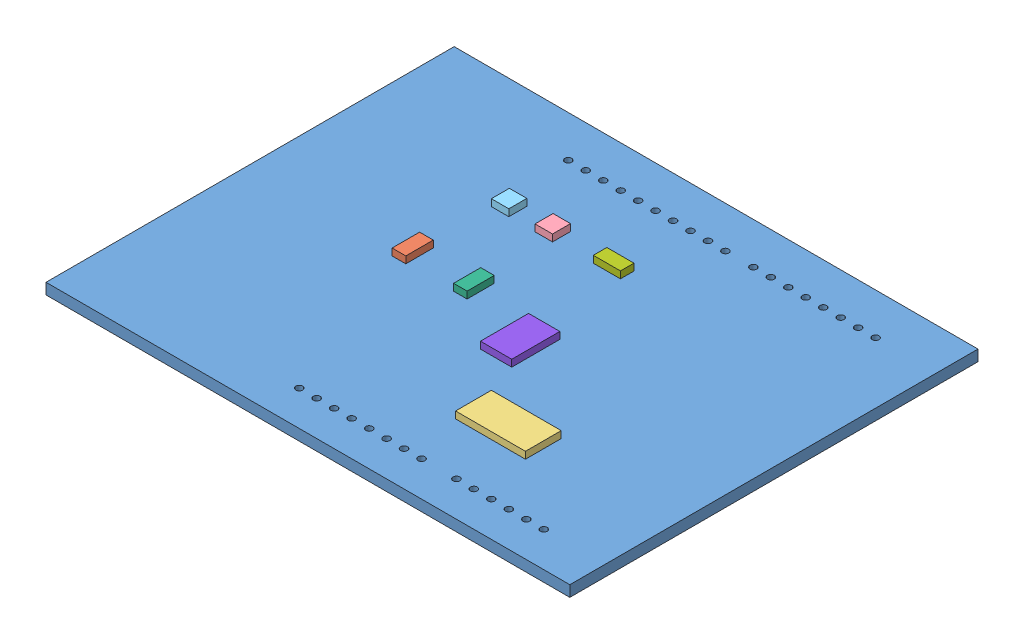
SolidWorks assembly PCB_Assembly, configuration Default. Lengths in mm.
Overall size (76.18 2.6 59.36).
8 component instances, 8 part files, 0 mates.
Components (placement in the parent):
- initial_schematic-1: initial_schematic [Default] x (1 0 0) z (0 1 0) size (76.18 59.36 1.6)
- C0805_C1_C0805-1: C0805_C1_C0805 [Default] at (57.15 1.6 -41.91) x (0 0 -1) z (0 1 0) size (4 1.99 1)
- AB9V_AB9V-1: AB9V_AB9V [Default] at (86.36 1.6 -26.67) x (0 0 -1) z (0 1 0) size (5.21 10.16 1)
- 1X01_JP1_1X01-1: 1X01_JP1_1X01 [Default] at (64.77 1.6 -54.61) x (1 0 0) z (0 1 0) size (2.54 2.62 1)
- 1X01_JP2_1X01-1: 1X01_JP2_1X01 [Default] at (58.42 1.6 -54.61) x (1 0 0) z (0 1 0) size (2.54 2.62 1)
- R0805W_50000-1: R0805W_50000 [Default] at (66.04 1.6 -41.91) x (0 0 1) z (0 1 0) size (3.95 1.97 1)
- R0805W_200-1: R0805W_200 [Default] at (73.66 1.6 -54.61) x (1 0 0) z (0 1 0) size (3.95 1.97 1)
- BTN_CK_KSS_SW1_BTN_CK_KSS-1: BTN_CK_KSS_SW1_BTN_CK_KSS [Default] at (76.2 1.6 -38.1) x (0 0 -1) z (0 1 0) size (7 4.55 1)
